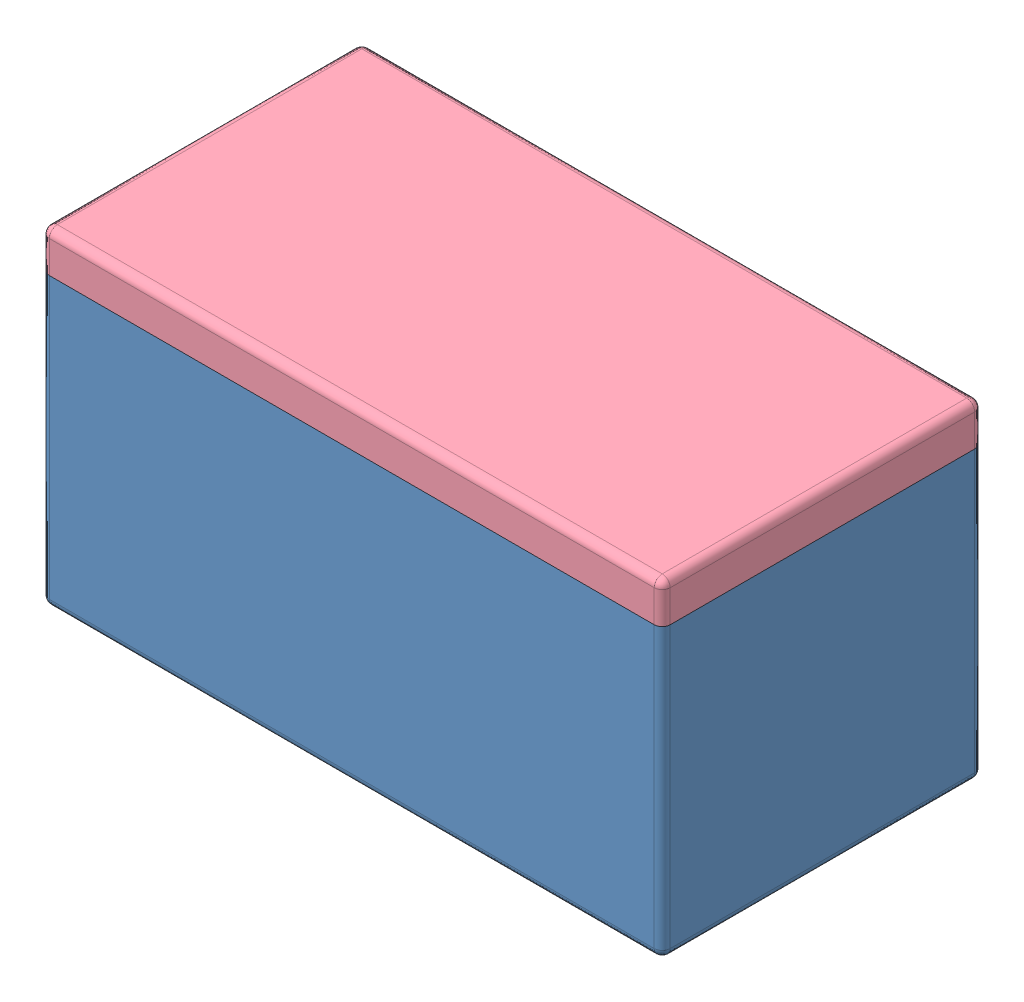
SolidWorks assembly Assem1, configuration Default. Lengths in mm.
Overall size (155 82 80).
4 component instances, 4 part files, 9 mates.
Components (placement in the parent):
- Base-1: Base [Default] at origin size (155 75 80)
- Baffle_A-2: Baffle_A [Default] at (-74 10 5) x (0 0 1) z (-1 0 0) size (40 65 15.5)
- Baffle_B-2: Baffle_B [Default] at (-70 10 75) x (0 0 1) z (-1 0 0) size (35 65 15.5)
- Top-1: Top [Default] at (-155 82 80) size (155 10 80)
Mates (geometry in assembly coordinates):
- Concentric2: concentric: circle of Baffle_A-2; circle of Baffle_B-2
- Coincident8: coincident: plane of Baffle_A-2 through (-70 25 40) normal (0 0 1); plane of Baffle_B-2 through (-82.5 25 40) normal (0 0 -1)
- Coincident9: coincident: plane of Base-1 through (-85 10 5) normal (0 0 1); plane of Baffle_A-2 through (-70 10 5) normal (0 0 -1)
- Coincident11: coincident: plane of Baffle_A-2 through (-70 10 5) normal (1 0 0); plane of Baffle_B-2 through (-70 10 75) normal (1 0 0)
- Coincident12: coincident: plane of Base-1 through (0 10 0) normal (0 1 0); plane of Baffle_B-2 through (-82.5 10 40) normal (0 -1 0)
- Coincident13: coincident: plane of Base-1 through (-70 10 5) normal (-1 0 0); plane of Baffle_A-2 through (-70 10 5) normal (1 0 0)
- Coincident16: coincident: plane of Base-1 through (-155 15 0) normal (-1 0 0); plane of Top-1 through (-155 77 80) normal (-1 0 0)
- Coincident18: coincident: plane of Base-1 through (0 15 0) normal (0 0 -1); plane of Top-1 through (-155 77 0) normal (0 0 -1)
- Coincident19: coincident: plane of Base-1 through (0 72 0) normal (0 1 0); plane of Top-1 through (-155 72 80) normal (0 -1 0)
